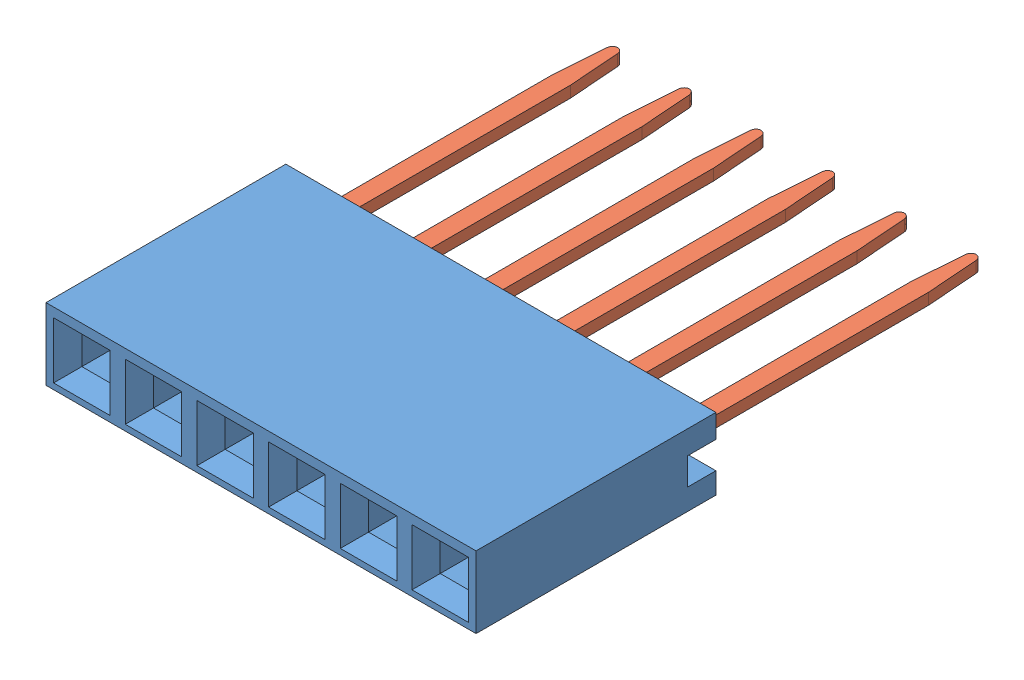
SolidWorks assembly 960240-6202-AR 1x6 long, configuration Default. Lengths in mm.
Overall size (15.24 2.54 18.99).
7 component instances, 2 part files, 4 mates.
Components (placement in the parent):
- 960240-6202-AR Body6-1: 960240-6202-AR Body6 [Default] at (7.62 -1.27 8.5) size (15.24 2.54 8.5)
- 960240-6202-AR Pin Long-1: 960240-6202-AR Pin Long [Default] at (6.35 0.04 -0.7572) x (1 0 0) z (0 -1 0) size (2 16.99 0.4)
- 960240-6202-AR Pin Long-3: 960240-6202-AR Pin Long [Default] at (3.81 0.04 -0.7572) x (1 0 0) z (0 -1 0) size (2 16.99 0.4)
- 960240-6202-AR Pin Long-5: 960240-6202-AR Pin Long [Default] at (1.27 0.04 -0.7572) x (1 0 0) z (0 -1 0) size (2 16.99 0.4)
- 960240-6202-AR Pin Long-7: 960240-6202-AR Pin Long [Default] at (-1.27 0.04 -0.7572) x (1 0 0) z (0 -1 0) size (2 16.99 0.4)
- 960240-6202-AR Pin Long-9: 960240-6202-AR Pin Long [Default] at (-3.81 0.04 -0.7572) x (1 0 0) z (0 -1 0) size (2 16.99 0.4)
- 960240-6202-AR Pin Long-11: 960240-6202-AR Pin Long [Default] at (-6.35 0.04 -0.7572) x (1 0 0) z (0 -1 0) size (2 16.99 0.4)
Mates (geometry in assembly coordinates):
- Coincident1: coincident anti-aligned: plane of 960240-6202-AR Pin Long-1 through (6.3656 -0.16 -10.2904) normal (0 -1 0); plane of 960240-6202-AR Body6-1 through (5.35 -0.16 6.5) normal (0 1 0)
- Tangent1: tangent anti-aligned: plane of 960240-6202-AR Body6-1 through (7.62 -1.27 6.5) normal (0 0 -1); cylinder of 960240-6202-AR Pin Long-1 through (7.15 0.24 6.3) axis (0 -1 0) radius 0.2
- Coincident2: coincident anti-aligned: plane of 960240-6202-AR Body6-1 through (7.35 -0.16 6.5) normal (-1 0 0); plane of 960240-6202-AR Pin Long-1 through (7.35 0.24 0.9096) normal (1 0 0)
- Coincident5: coordinate: unknown of 960240-6202-AR Body6-1
